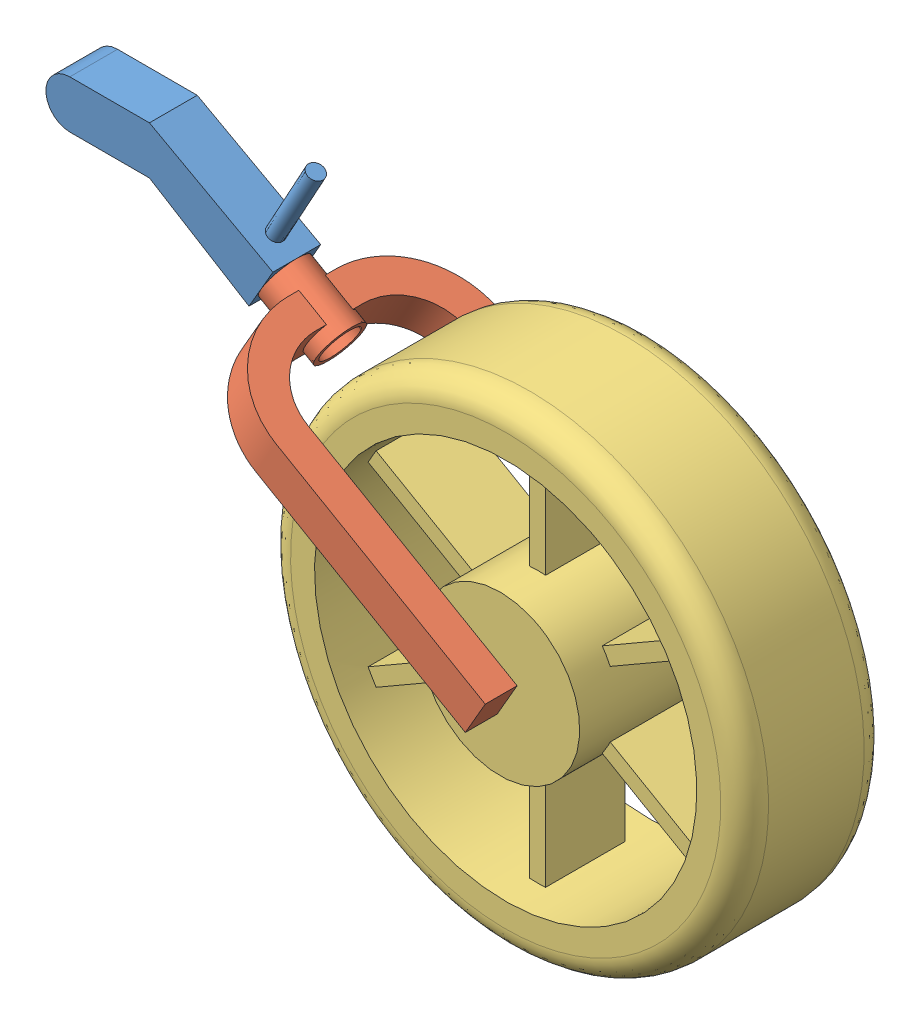
SolidWorks assembly Amortecimento&Motor, configuration Default. Lengths in mm.
Overall size (523.5 434.65 142.03).
4 component instances, 3 part files, 6 mates.
Components (placement in the parent):
- Suporte_Rodas-1: Suporte_Rodas [Default] at origin size (166.98 93.59 30)
- Chave&Motor-1: Chave&Motor [Default] at (303.5974 -146.4145 0) x (0 0 1) z (-0.5 -0.866025 0) size (142.03 362 300)
  - Chave_Motor-1: Chave_Motor [Default] at origin size (142.03 220 30)
  - Motor_Roda-2: Motor_Roda [Default] x (0 0 -1) z (1 0 0) size (300 300 97)
Mates (geometry in assembly coordinates):
- Concentric1: concentric: cylinder of Suporte_Rodas-1 through (145.9808 -55.4145 0) axis (-0.866025 0.5 0) radius 12; cylinder of Chave&Motor-1/Chave_Motor-1 through (310.5256 -150.4145 0) axis (-0.866025 0.5 0) radius 12
- Coincident1: coincident: circle of Suporte_Rodas-1; circle of Chave&Motor-1/Chave_Motor-1
- Coincident2: coincident: plane of Suporte_Rodas-1 through (0 0 0) normal (0 0 1); plane of Chave&Motor-1/Chave_Motor-1 through (303.5974 -146.4145 0) normal (0 0 1)
- Coincident3: coincident: plane of Suporte_Rodas-1 through (0 0 0) normal (0 0 1); plane of assembly through (0 0 0) normal (0 0 1)
- Coincident4: coincident: plane of Suporte_Rodas-1 through (0 0 0) normal (0 1 0); plane of assembly through (0 0 0) normal (0 1 0)
- Coincident5: coincident: plane of Suporte_Rodas-1 through (0 0 0) normal (1 0 0); plane of assembly through (0 0 0) normal (1 0 0)
